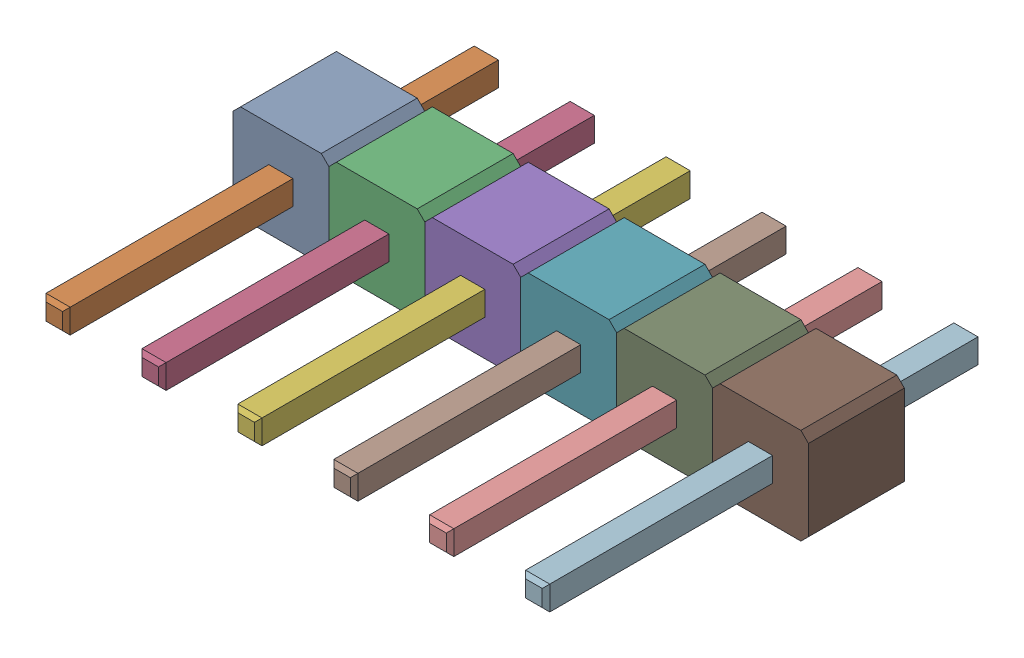
SolidWorks assembly XP1, configuration По умолчанию. Lengths in mm.
Overall size (15.24 2.54 11.54).
3 component instances, 1 part files, 0 mates.
Components (placement in the parent):
- User_Library-PLS-2-1: User_Library-PLS-2 [По умолчанию] at (19.9299 -25.8001 0) x (1 0 0) z (0 -1 0) size (5.08 11.54 2.54)
- User_Library-PLS-2-2: User_Library-PLS-2 [По умолчанию] at (25.0099 -25.8001 0) x (1 0 0) z (0 -1 0) size (5.08 11.54 2.54)
- User_Library-PLS-2-3: User_Library-PLS-2 [По умолчанию] at (30.0899 -25.8001 0) x (1 0 0) z (0 -1 0) size (5.08 11.54 2.54)
